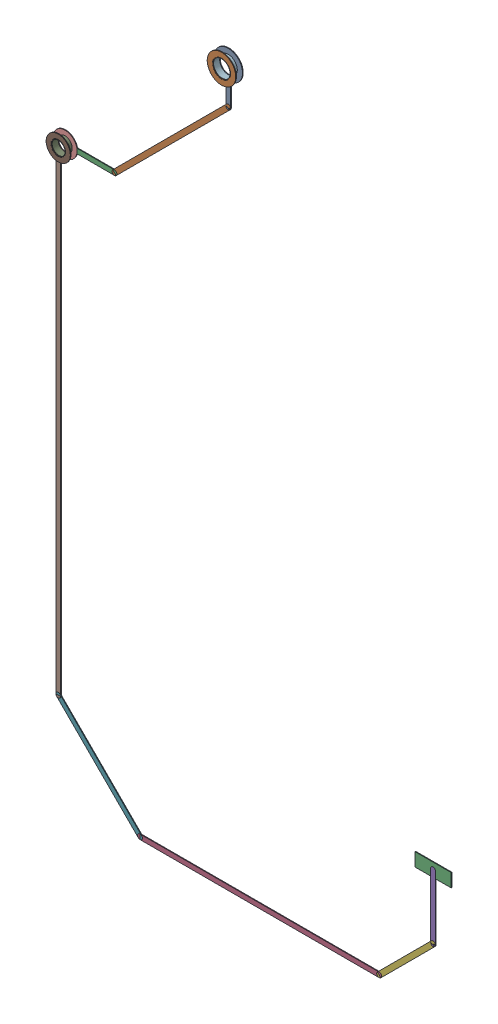
SolidWorks assembly RX, configuration Predeterminado. Lengths in mm.
Overall size (21.29 37.98 0.39).
41 component instances, 13 part files, 0 mates.
Components (placement in the parent):
- Track (18.08mm,41.48mm)(18.08mm,43.4mm) on Bottom Layer-1: Track (18.08mm,41.48mm)(18.08mm,43.4mm) on Bottom Layer [Predeterminado] at origin size (0.25 1.62 0.04)
  - Track (18.08mm,41.48mm)(18.08mm,43.4mm) on Bottom Layer-1-1: Track (18.08mm,41.48mm)(18.08mm,43.4mm) on Bottom Layer-1 [Predeterminado] at (-68.317 -44.187 -0.4013) size (0.25 1.62 0.04)
    - Track (18.08mm,41.48mm)(18.08mm,43.4mm) on Bottom Layer-Part-1-1: Track (18.08mm,41.48mm)(18.08mm,43.4mm) on Bottom Layer-Part-1 [Predeterminado] at origin size (0.25 1.62 0.04)
- Track (12.1mm,35.5mm)(18.08mm,41.48mm) on Bottom Layer-1: Track (12.1mm,35.5mm)(18.08mm,41.48mm) on Bottom Layer [Predeterminado] at origin size (6.23 6.23 0.04)
  - Track (12.1mm,35.5mm)(18.08mm,41.48mm) on Bottom Layer-1-1: Track (12.1mm,35.5mm)(18.08mm,41.48mm) on Bottom Layer-1 [Predeterminado] at (-68.317 -44.187 -0.4013) size (6.23 6.23 0.04)
    - Track (12.1mm,35.5mm)(18.08mm,41.48mm) on Bottom Layer-Part-1-1: Track (12.1mm,35.5mm)(18.08mm,41.48mm) on Bottom Layer-Part-1 [Predeterminado] at origin size (6.23 6.23 0.04)
- Track (9.5mm,35.5mm)(12.1mm,35.5mm) on Bottom Layer-1: Track (9.5mm,35.5mm)(12.1mm,35.5mm) on Bottom Layer [Predeterminado] at origin size (2.39 0.25 0.04)
  - Track (9.5mm,35.5mm)(12.1mm,35.5mm) on Bottom Layer-1-1: Track (9.5mm,35.5mm)(12.1mm,35.5mm) on Bottom Layer-1 [Predeterminado] at (-68.317 -44.187 -0.4013) size (2.39 0.25 0.04)
    - Track (9.5mm,35.5mm)(12.1mm,35.5mm) on Bottom Layer-Part-1-1: Track (9.5mm,35.5mm)(12.1mm,35.5mm) on Bottom Layer-Part-1 [Predeterminado] at origin size (2.39 0.25 0.04)
- Track (13.8mm,6.3mm)(26.366mm,6.3mm) on Top Layer-1: Track (13.8mm,6.3mm)(26.366mm,6.3mm) on Top Layer [Predeterminado] at origin size (12.82 0.25 0.04)
  - Track (13.8mm,6.3mm)(26.366mm,6.3mm) on Top Layer-1-1: Track (13.8mm,6.3mm)(26.366mm,6.3mm) on Top Layer-1 [Predeterminado] at (-68.317 -44.187 -0.0457) size (12.82 0.25 0.04)
    - Track (13.8mm,6.3mm)(26.366mm,6.3mm) on Top Layer-Part-1-1: Track (13.8mm,6.3mm)(26.366mm,6.3mm) on Top Layer-Part-1 [Predeterminado] at origin size (12.82 0.25 0.04)
- Track (29.2mm,9.134mm)(29.2mm,12.5mm) on Top Layer-1: Track (29.2mm,9.134mm)(29.2mm,12.5mm) on Top Layer [Predeterminado] at origin size (0.25 3.62 0.04)
  - Track (29.2mm,9.134mm)(29.2mm,12.5mm) on Top Layer-1-1: Track (29.2mm,9.134mm)(29.2mm,12.5mm) on Top Layer-1 [Predeterminado] at (-68.317 -44.187 -0.0457) size (0.25 3.62 0.04)
    - Track (29.2mm,9.134mm)(29.2mm,12.5mm) on Top Layer-Part-1-1: Track (29.2mm,9.134mm)(29.2mm,12.5mm) on Top Layer-Part-1 [Predeterminado] at origin size (0.25 3.62 0.04)
- Track (26.366mm,6.3mm)(29.2mm,9.134mm) on Top Layer-1: Track (26.366mm,6.3mm)(29.2mm,9.134mm) on Top Layer [Predeterminado] at origin size (3.09 3.09 0.04)
  - Track (26.366mm,6.3mm)(29.2mm,9.134mm) on Top Layer-1-1: Track (26.366mm,6.3mm)(29.2mm,9.134mm) on Top Layer-1 [Predeterminado] at (-68.317 -44.187 -0.0457) size (3.09 3.09 0.04)
    - Track (26.366mm,6.3mm)(29.2mm,9.134mm) on Top Layer-Part-1-1: Track (26.366mm,6.3mm)(29.2mm,9.134mm) on Top Layer-Part-1 [Predeterminado] at origin size (3.09 3.09 0.04)
- Track (9.5mm,10.6mm)(13.8mm,6.3mm) on Top Layer-1: Track (9.5mm,10.6mm)(13.8mm,6.3mm) on Top Layer [Predeterminado] at origin size (4.55 4.55 0.04)
  - Track (9.5mm,10.6mm)(13.8mm,6.3mm) on Top Layer-1-1: Track (9.5mm,10.6mm)(13.8mm,6.3mm) on Top Layer-1 [Predeterminado] at (-68.317 -44.187 -0.0457) size (4.55 4.55 0.04)
    - Track (9.5mm,10.6mm)(13.8mm,6.3mm) on Top Layer-Part-1-1: Track (9.5mm,10.6mm)(13.8mm,6.3mm) on Top Layer-Part-1 [Predeterminado] at origin size (4.55 4.55 0.04)
- Track (9.5mm,10.6mm)(9.5mm,35.5mm) on Top Layer-1: Track (9.5mm,10.6mm)(9.5mm,35.5mm) on Top Layer [Predeterminado] at origin size (0.25 24.69 0.04)
  - Track (9.5mm,10.6mm)(9.5mm,35.5mm) on Top Layer-1-1: Track (9.5mm,10.6mm)(9.5mm,35.5mm) on Top Layer-1 [Predeterminado] at (-68.317 -44.187 -0.0457) size (0.25 24.69 0.04)
    - Track (9.5mm,10.6mm)(9.5mm,35.5mm) on Top Layer-Part-1-1: Track (9.5mm,10.6mm)(9.5mm,35.5mm) on Top Layer-Part-1 [Predeterminado] at origin size (0.25 24.69 0.04)
- Via (9.5mm,35.5mm) from Top Layer to Bottom Layer-1: Via (9.5mm,35.5mm) from Top Layer to Bottom Layer [Predeterminado] at origin size (1.27 1.27 0.39)
  - Via Hole-1: Via Hole [Predeterminado] at (9.5 35.5 -0.4013) size (0.76 0.76 0.39)
    - Via Hole-Part-1-1: Via Hole-Part-1 [Predeterminado] at origin size (0.76 0.76 0.39)
  - Via Top Layer-1: Via Top Layer [Predeterminado] at (9.5 35.5 -0.4013) size (1.27 1.27 0.04)
    - Via Top Layer-Part-1-1: Via Top Layer-Part-1 [Predeterminado] at origin size (1.27 1.27 0.04)
  - Via Top Layer-2: Via Top Layer [Predeterminado] at (9.5 35.5 -0.0457) size (1.27 1.27 0.04)
    - Via Top Layer-Part-1-1: Via Top Layer-Part-1 [Predeterminado] at origin size (1.27 1.27 0.04)
- Pad UART-3(18.08mm,43.4mm) on Multi-Layer-1: Pad UART-3(18.08mm,43.4mm) on Multi-Layer [Predeterminado] at origin size (1.5 1.5 0.39)
  - Pad Hole-1-1: Pad Hole-1 [Predeterminado] at (18.08 43.4 -0.4013) size (0.95 0.95 0.39)
    - Pad Hole-Part-1-1-1: Pad Hole-Part-1-1 [Predeterminado] at origin size (0.95 0.95 0.39)
  - Top Layer-1-1: Top Layer-1 [Predeterminado] at (18.08 43.4 -0.4013) size (1.5 1.5 0.04)
    - Top Layer-Part-1-1-1: Top Layer-Part-1-1 [Predeterminado] at origin size (1.5 1.5 0.04)
  - Top Layer-1-2: Top Layer-1 [Predeterminado] at (18.08 43.4 -0.0457) size (1.5 1.5 0.04)
    - Top Layer-Part-1-1-1: Top Layer-Part-1-1 [Predeterminado] at origin size (1.5 1.5 0.04)
- Pad RAK4600-22(29.2mm,12.5mm) on Top Layer-1: Pad RAK4600-22(29.2mm,12.5mm) on Top Layer [Predeterminado] at origin size (1.9 0.7 0.04)
  - Pad RAK4600-22(29.2mm,12.5mm) on Top Layer-1-1: Pad RAK4600-22(29.2mm,12.5mm) on Top Layer-1 [Predeterminado] at (-68.317 -44.187 -0.0457) size (1.9 0.7 0.04)
    - Pad RAK4600-22(29.2mm,12.5mm) on Top Layer-Part-1-1: Pad RAK4600-22(29.2mm,12.5mm) on Top Layer-Part-1 [Predeterminado] at origin size (1.9 0.7 0.04)
